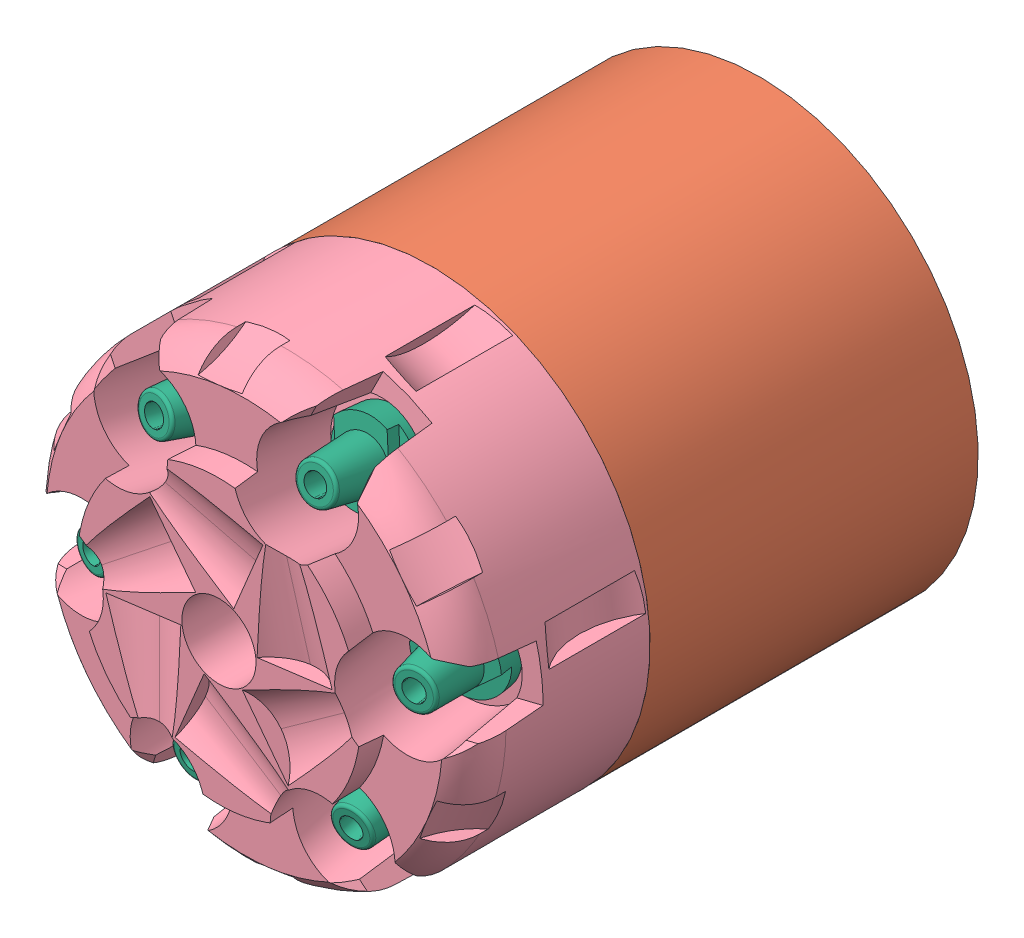
SolidWorks assembly Cylinder_cut_inner_piston.38, configuration Default. Lengths in mm.
Overall size (59.68 59.46 52.12).
21 component instances, 6 part files, 24 mates.
Components (placement in the parent):
- Piston.38-1: Piston.38 [Default] at (7.4297 37.7594 53.3035) x (0.99879 -0.049172 0) z (0 0 -1) size (8.64 8.64 17)
- Piston.38-2: Piston.38 [Default] at (-5.1664 36.1376 53.3035) x (0.541979 0.840392 0) z (0 0 -1) size (8.64 8.64 17)
- Piston.38-3: Piston.38 [Default] at (-10.0599 24.4183 53.3035) x (-0.456811 0.889564 0) z (0 0 -1) size (8.64 8.64 17)
- Piston.38-4: Piston.38 [Default] at (-2.3574 14.3207 53.3035) x (-0.99879 0.049172 0) z (0 0 -1) size (8.64 8.64 17)
- Piston.38-5: Piston.38 [Default] at (10.2386 15.9424 53.3035) x (-0.541979 -0.840392 0) z (0 0 -1) size (8.64 8.64 17)
- Piston.38-6: Piston.38 [Default] at (15.1322 27.6618 53.3035) x (0.456811 -0.889564 0) z (0 0 -1) size (8.64 8.64 17)
- Cylinder_cut.38-1: Cylinder_cut.38 [Default] at (-7.6261 -6.3953 7.6816) size (43.32 43.9 52.12)
- Inner_cylinder.38-7: Inner_cylinder.38 [Default] at (15.1322 27.6618 32.0299) size (9.65 9.65 21.34)
- Inner_cylinder.38-8: Inner_cylinder.38 [Default] at (7.4297 37.7594 32.0299) x (0.5 0.866025 0) z (0 0 1) size (9.65 9.65 21.34)
- Inner_cylinder.38-9: Inner_cylinder.38 [Default] at (-5.1664 36.1376 32.0299) x (-0.5 0.866025 0) z (0 0 1) size (9.65 9.65 21.34)
- Inner_cylinder.38-10: Inner_cylinder.38 [Default] at (-10.0599 24.4183 32.0299) x (-1 0 0) z (0 0 1) size (9.65 9.65 21.34)
- Inner_cylinder.38-11: Inner_cylinder.38 [Default] at (-2.3574 14.3207 32.0299) x (-0.5 -0.866025 0) z (0 0 1) size (9.65 9.65 21.34)
- Inner_cylinder.38-12: Inner_cylinder.38 [Default] at (10.2386 15.9424 32.0299) x (0.5 -0.866025 0) z (0 0 1) size (9.65 9.65 21.34)
- Back_part_of_cylinder-3: Back_part_of_cylinder [Default] at (10.1638 32.5897 38.8919) x (0.5 -0.866025 0) z (0 0 1) size (43.32 43.9 21.29)
- Peg-2: Peg [Default] at (0.2657 43.6745 48.2859) x (0.999764 0.021735 0) z (0 0 1) size (2.54 2.54 10.16)
- Nippel-7: Nippel [Default] at (290.7895 260.7702 128.7446) x (-0.520932 -0.399214 -0.754492) z (-0.504442 0.857016 -0.105174) size (12.39 9.96 7.5)
- Nippel-8: Nippel [Default] at (-56.6195 393.0399 128.7446) x (0.085263 -0.650747 -0.754492) z (-0.994419 -0.008352 -0.105174) size (12.39 9.96 7.5)
- Nippel-9: Nippel [Default] at (-344.8729 158.3097 128.7446) x (0.606195 -0.251533 -0.754492) z (-0.489977 -0.865368 -0.105174) size (12.39 9.96 7.5)
- Nippel-10: Nippel [Default] at (-285.7173 -208.6902 128.7446) x (0.520932 0.399214 -0.754492) z (0.504442 -0.857016 -0.105174) size (12.39 9.96 7.5)
- Nippel-11: Nippel [Default] at (61.6917 -340.9598 128.7446) x (-0.085263 0.650747 -0.754492) z (0.994419 0.008352 -0.105174) size (12.39 9.96 7.5)
- Nippel-12: Nippel [Default] at (349.9452 -106.2296 128.7446) x (-0.606195 0.251533 -0.754492) z (0.489977 0.865368 -0.105174) size (12.39 9.96 7.5)
Mates (geometry in assembly coordinates):
- Lock1: lock: unknown of Piston.38-1; unknown of Cylinder_cut.38-1
- Lock8: lock: unknown of Piston.38-3; unknown of Cylinder_cut.38-1
- Lock9: lock: unknown of Piston.38-2; unknown of Cylinder_cut.38-1
- Lock10: lock: unknown of Piston.38-1; unknown of Cylinder_cut.38-1
- Lock11: lock: unknown of Piston.38-6; unknown of Cylinder_cut.38-1
- Lock12: lock: unknown of Piston.38-5; unknown of Cylinder_cut.38-1
- Lock13: lock: unknown of Piston.38-4; unknown of Cylinder_cut.38-1
- Lock17: lock: unknown of Piston.38-1; unknown of Cylinder_cut.38-1
- Lock18: lock: unknown of Piston.38-2; unknown of Cylinder_cut.38-1
- Lock19: lock: unknown of Piston.38-5; unknown of Cylinder_cut.38-1
- Lock20: lock: unknown of Piston.38-4; unknown of Cylinder_cut.38-1
- Lock21: lock: unknown of Piston.38-3; unknown of Cylinder_cut.38-1
- Concentric2: concentric: circle of Cylinder_cut.38-1; cylinder of Inner_cylinder.38-7 through (15.1322 27.6618 63.0179) axis (0 0 -1) radius 4.826
- Coincident3: coincident: plane of Cylinder_cut.38-1 through (-26.8977 53.6047 53.3659) normal (0 0 1); plane of Inner_cylinder.38-7 through (15.1322 27.6618 53.3659) normal (0 0 1)
- Lock22: lock: unknown of Cylinder_cut.38-1
- Concentric7: concentric: cylinder of Cylinder_cut.38-1 through (2.5361 26.04 47.8808) axis (0 0 1) radius 3.5; cylinder of Back_part_of_cylinder-3 through (2.5361 26.04 47.8809) axis (0 0 1) radius 3.5
- Concentric8: concentric: cylinder of Cylinder_cut.38-1 through (0.2657 43.6745 48.2859) axis (0 0 1) radius 1.27; cylinder of Peg-2 through (0.2657 43.6745 58.4459) axis (0 0 -1) radius 1.27
- Distance2: distance = 5.08 mm: plane of Peg-2 through (0.2657 43.6745 58.4459) normal (0 0 1); plane of Cylinder_cut.38-1 through (-26.8977 53.6047 53.3659) normal (0 0 1)
- Concentric9: concentric: cylinder of Cylinder_cut.38-1 through (2.5361 26.04 47.8808) axis (0 0 1) radius 3.5; cylinder of Back_part_of_cylinder-3 through (2.5361 26.04 47.8809) axis (0 0 1) radius 3.5
- Concentric10: concentric: cylinder of Cylinder_cut.38-1 through (2.5361 26.04 47.8808) axis (0 0 1) radius 20.7; cylinder of Back_part_of_cylinder-3 through (2.5361 26.04 47.8809) axis (0 0 1) radius 20.7
- Concentric11: concentric: cylinder of Back_part_of_cylinder-3 through (0.2657 43.6745 58.4459) axis (0 0 -1) radius 1.27; cylinder of Peg-2 through (0.2657 43.6745 58.4459) axis (0 0 -1) radius 1.27
- Distance3: distance = 0 mm: plane of Back_part_of_cylinder-3 through (8.4362 60.3444 53.3659) normal (0 0 -1); plane of Cylinder_cut.38-1 through (-26.8977 53.6047 53.3659) normal (0 0 1)
- Concentric12: concentric: cylinder of Back_part_of_cylinder-3 through (8.5019 40.3272 70.8825) axis (-0.06691 -0.16024 -0.984808) radius 2.067; cylinder of Nippel-7 through (8.0469 39.2375 64.1858) axis (0.06691 0.16024 0.984808) radius 2.5
- Coincident4: coincident: plane of Back_part_of_cylinder-3 through (6.0659 39.8577 63.1025) normal (0.06691 0.16024 0.984808); plane of Nippel-7 through (6.1031 38.1468 63.3783) normal (-0.06691 -0.16024 -0.984808)
